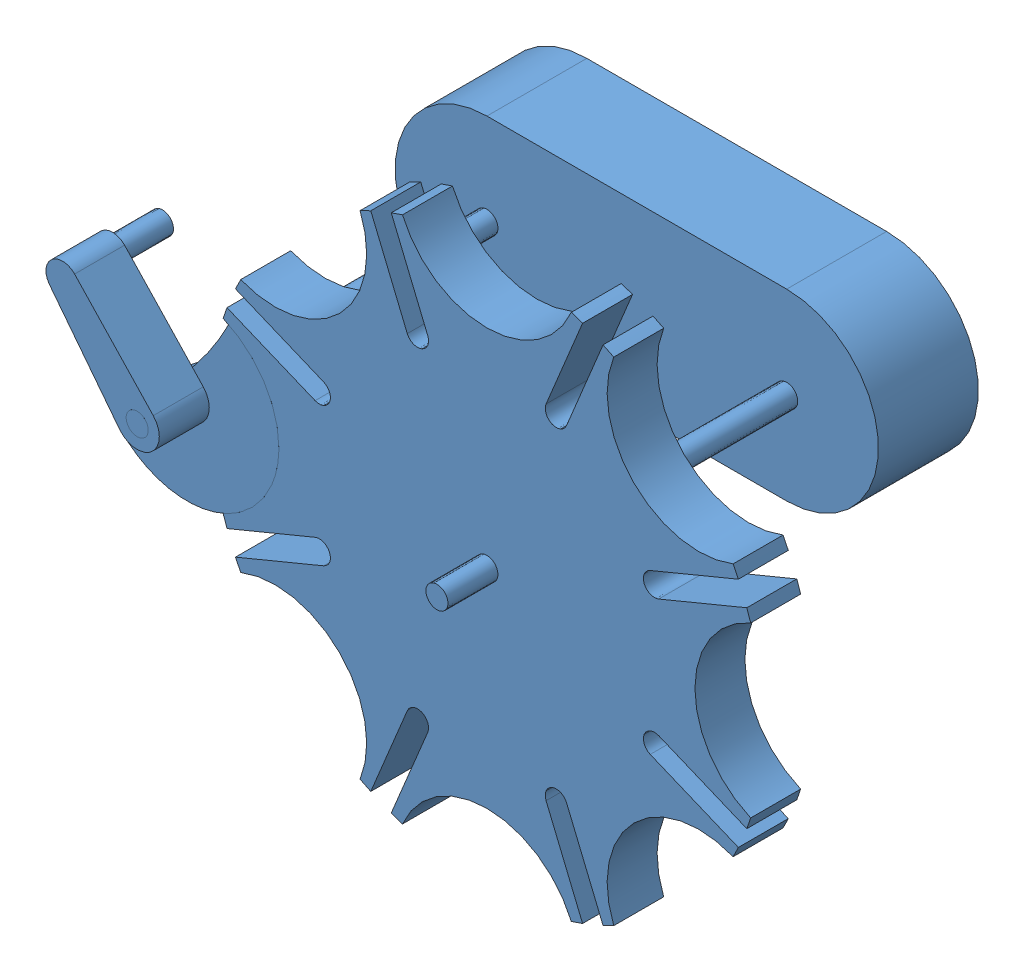
SolidWorks assembly Ensamble_Rueda_Ginebra_M, configuration Default. Lengths in mm.
Overall size (42.9 31.68 27).
3 component instances, 1 part files, 4 mates.
Components (placement in the parent):
- Rueda_Ginebra_5-3: Rueda_Ginebra_5 [Soporte] at (33.8881 0.3396 25.4558) size (29.02 11.02 27)
- Rueda_Ginebra_5-4: Rueda_Ginebra_5 [Disco_bloqueador] at (24.0354 16.3902 25.4558) x (0.452629 0.891699 0) z (0 0 1) size (11.02 12.87 6)
- Rueda_Ginebra_5-5: Rueda_Ginebra_5 [Default] at (33.8881 0.3396 25.4558) size (31.68 31.68 3)
Mates (geometry in assembly coordinates):
- Coincidente1: coincident: plane of Rueda_Ginebra_5-3 through (15.8881 0.3396 28.4558) normal (0 0 1); plane of Rueda_Ginebra_5-4 through (15.8881 0.3396 28.4558) normal (0 0 1)
- Concéntrica1: concentric: circle of Rueda_Ginebra_5-3; circle of Rueda_Ginebra_5-4
- Coincidente3: coincident: plane of Rueda_Ginebra_5-4 through (15.8881 0.3396 25.4558) normal (0 0 -1); plane of Rueda_Ginebra_5-5 through (33.8881 0.3396 25.4558) normal (0 0 1)
- Concéntrica2: concentric: circle of Rueda_Ginebra_5-3; circle of Rueda_Ginebra_5-5
